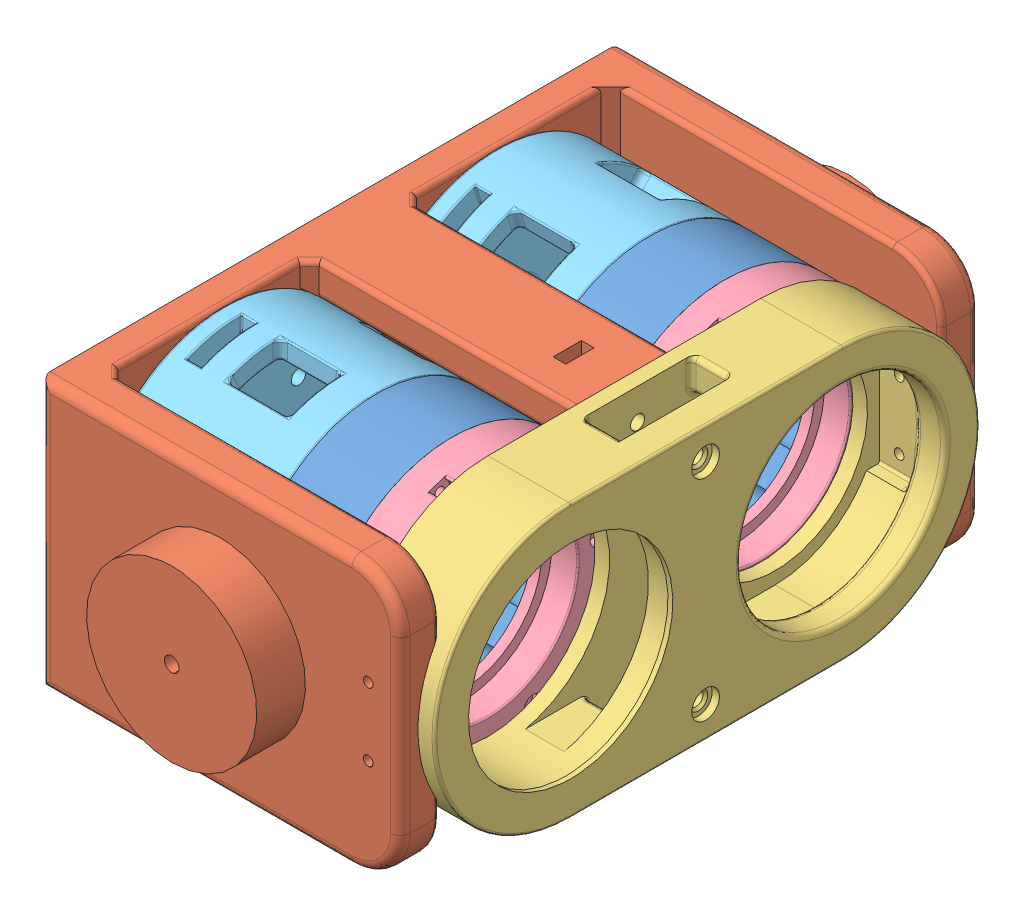
SolidWorks assembly RB_JIAN_LINK, configuration 默认. Lengths in mm.
Overall size (77.4 98.63 139.2).
8 component instances, 5 part files, 15 mates.
Components (placement in the parent):
- 减速器壳体-1: 减速器壳体 [默认] at (55 -1 121.9) x (0 0.991122 0.132958) z (1 0 0) size (55.2 55.2 15.5)
- 减速器壳体-2: 减速器壳体 [默认] at (55 -1 65.9) x (0 0.991122 0.132958) z (1 0 0) size (55.2 55.2 15.5)
- 支撑架-1: 支撑架 [默认] at (17 -1 93.9) x (0 0 -1) z (0 1 0) size (139.2 74 55.2)
- 保持架-1: 保持架 [默认] at (87.4 -1 121.9) x (0 0 -1) z (0 1 0) size (112 17 56)
- 减速器上盖-1: 减速器上盖 [默认] at (69.5 -1 65.9) x (0 0.97778 -0.209635) z (-1 0 0) size (55.2 55.2 7.4)
- 电机座-1: 电机座 [默认] at (48.5 -1 65.9) x (0 0.473915 -0.88057) z (-1 0 0) size (55.2 55.2 31.5)
- 减速器上盖-2: 减速器上盖 [默认] at (69.5 -1 121.9) x (0 0.97778 -0.209635) z (-1 0 0) size (55.2 55.2 7.4)
- 电机座-2: 电机座 [默认] at (48.5 -1 121.9) x (0 0.199902 -0.979816) z (-1 0 0) size (55.2 55.2 31.5)
Mates (geometry in assembly coordinates):
- 同心626: concentric aligned: cylinder of 支撑架-1 through (70 -1 121.9) axis (1 0 0) radius 28; cylinder of 保持架-1 through (82.4 -1 121.9) axis (1 0 0) radius 28
- 同心627: concentric aligned: cylinder of 支撑架-1 through (70 -1 65.9) axis (1 0 0) radius 28; cylinder of 保持架-1 through (82.4 -1 65.9) axis (1 0 0) radius 28
- 重合356: coincident anti-aligned: plane of 支撑架-1 through (71.4 -1 121.9) normal (1 0 0); plane of 保持架-1 through (71.4 -1 121.9) normal (-1 0 0)
- 同心621: concentric anti-aligned: cylinder of 减速器壳体-2 through (64 -1 65.9) axis (-1 0 0) radius 27.6; cylinder of 减速器上盖-1 through (64 -1 65.9) axis (1 0 0) radius 27.6
- 重合353: coincident anti-aligned: plane of 减速器壳体-2 through (64 -1 65.9) normal (1 0 0); plane of 减速器上盖-1 through (64 -1 65.9) normal (-1 0 0)
- 同心620: concentric anti-aligned: cylinder of 电机座-1 through (20.5 -1 65.9) axis (1 0 0) radius 27.6; cylinder of 减速器壳体-2 through (64 -1 65.9) axis (-1 0 0) radius 27.6
- 重合352: coincident anti-aligned: plane of 电机座-1 through (48.5 -1 65.9) normal (1 0 0); plane of 减速器壳体-2 through (48.5 -1 65.9) normal (-1 0 0)
- 同心625: concentric anti-aligned: cylinder of 支撑架-1 through (17 -1 65.9) axis (-1 0 0) radius 6; cylinder of 电机座-1 through (20.5 -1 65.9) axis (1 0 0) radius 27.6
- 重合355: coincident aligned: circle of 支撑架-1; plane of 电机座-1 through (17 -1 65.9) normal (-1 0 0)
- 同心619: concentric anti-aligned: cylinder of 减速器壳体-1 through (64 -1 121.9) axis (-1 0 0) radius 27.6; cylinder of 减速器上盖-2 through (64 -1 121.9) axis (1 0 0) radius 27.6
- 重合351: coincident anti-aligned: plane of 减速器壳体-1 through (64 -1 121.9) normal (1 0 0); plane of 减速器上盖-2 through (64 -1 121.9) normal (-1 0 0)
- 同心618: concentric anti-aligned: cylinder of 电机座-2 through (20.5 -1 121.9) axis (1 0 0) radius 27.6; cylinder of 减速器壳体-1 through (64 -1 121.9) axis (-1 0 0) radius 27.6
- 重合350: coincident anti-aligned: plane of 电机座-2 through (48.5 -1 121.9) normal (1 0 0); plane of 减速器壳体-1 through (48.5 -1 121.9) normal (-1 0 0)
- 同心624: concentric anti-aligned: cylinder of 支撑架-1 through (17 -1 121.9) axis (-1 0 0) radius 6; cylinder of 电机座-2 through (20.5 -1 121.9) axis (1 0 0) radius 27.6
- 重合354: coincident aligned: circle of 支撑架-1; plane of 电机座-2 through (17 -1 121.9) normal (-1 0 0)
